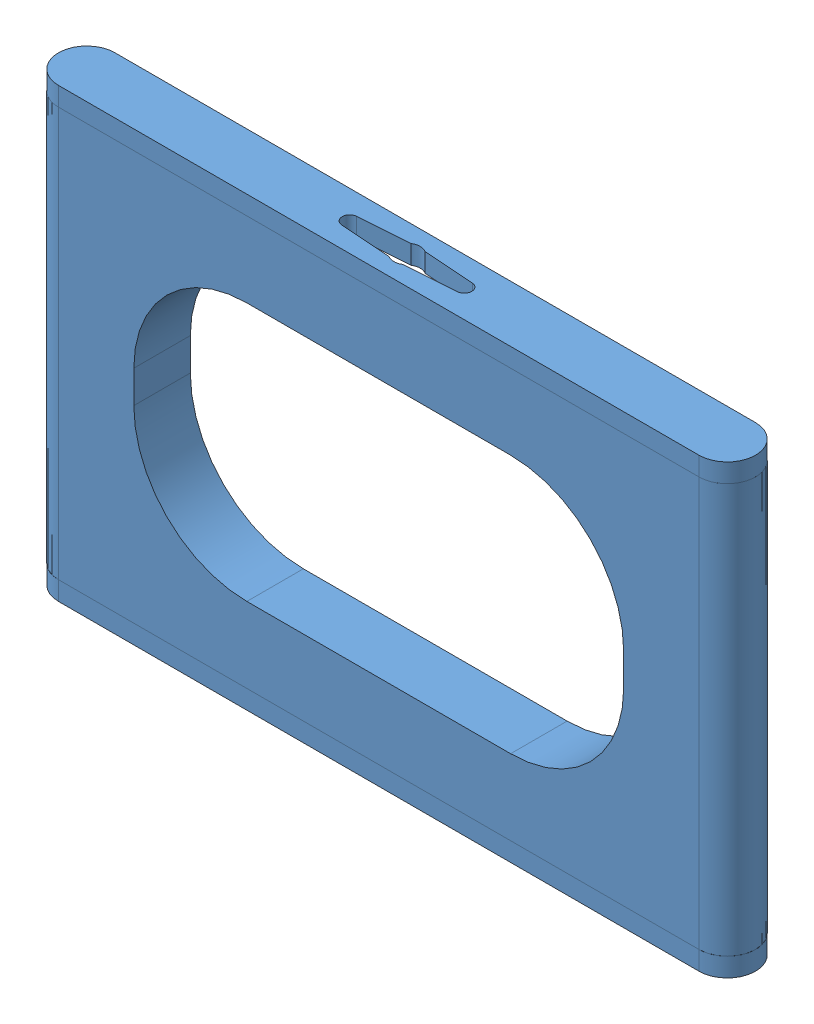
SolidWorks assembly Balance, configuration Default. Lengths in mm.
Overall size (185 118.6 15).
3 component instances, 1 part files, 6 mates.
Components (placement in the parent):
- Balance-1: Balance [Print] at (55.2159 60.3307 173.9085) size (185 108.6 15)
- Balance-2: Balance [Cut] at (55.2159 173.4307 173.9085) size (185 5 15)
- Balance-3: Balance [Cut] at (55.2159 59.8307 173.9085) size (185 5 15)
Mates (geometry in assembly coordinates):
- Concentric1: concentric aligned: cylinder of Balance-1 through (140.2159 177.9307 173.9085) axis (0 -1 0) radius 7.5; cylinder of Balance-2 through (140.2159 178.4307 173.9085) axis (0 -1 0) radius 7.5
- Concentric2: concentric aligned: cylinder of Balance-2 through (140.2159 178.4307 173.9085) axis (0 -1 0) radius 7.5; cylinder of Balance-3 through (140.2159 64.8307 173.9085) axis (0 -1 0) radius 7.5
- Concentric3: concentric aligned: cylinder of Balance-1 through (-29.7841 177.9307 173.9085) axis (0 -1 0) radius 7.5; cylinder of Balance-2 through (-29.7841 178.4307 173.9085) axis (0 -1 0) radius 7.5
- Concentric4: concentric aligned: cylinder of Balance-2 through (-29.7841 178.4307 173.9085) axis (0 -1 0) radius 7.5; cylinder of Balance-3 through (-29.7841 64.8307 173.9085) axis (0 -1 0) radius 7.5
- Coincident1: coincident anti-aligned: plane of Balance-1 through (-29.7841 173.4307 173.9085) normal (0 1 0); plane of Balance-2 through (55.2159 173.4307 173.9085) normal (0 -1 0)
- Coincident2: coincident anti-aligned: plane of Balance-1 through (105.2159 64.8307 178.4085) normal (0 -1 0); plane of Balance-3 through (55.2159 64.8307 173.9085) normal (0 1 0)
